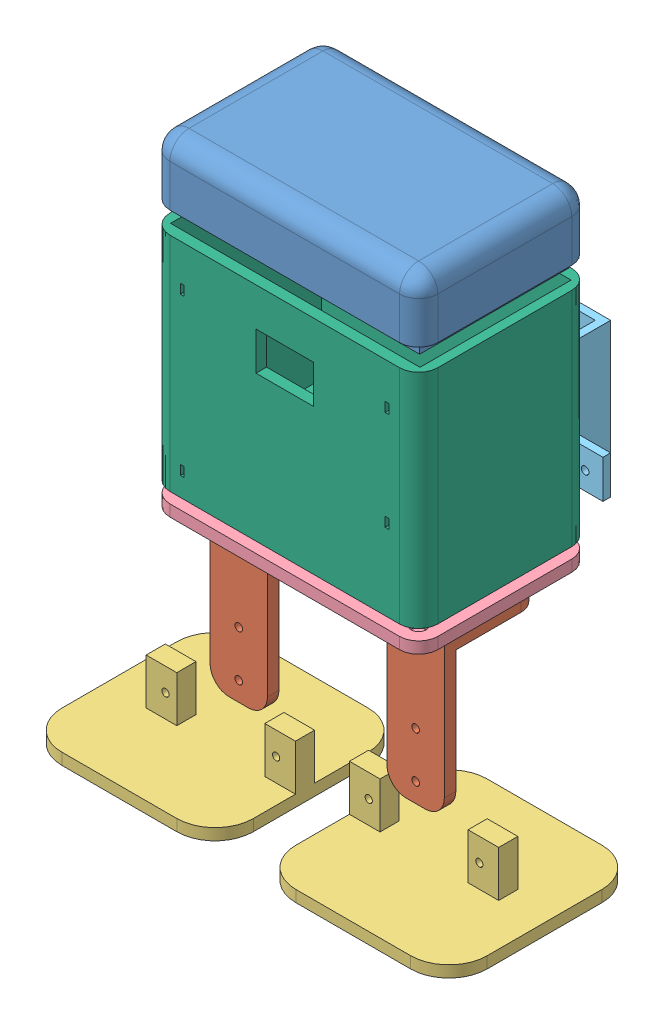
SolidWorks assembly 屏幕装配体, configuration 默认. Lengths in mm.
Overall size (111.6 142.57 75.38).
8 component instances, 6 part files, 9 mates.
Components (placement in the parent):
- 额头-1: 额头 [默认] at (-6.3922 22.1994 70) x (-1 0 0) z (0 0 1) size (70 19 45)
- 腿-1: 腿 [默认] at (-36.8922 -91.2045 78.5) size (15 40 25)
- 腿-2: 腿 [默认] at (9.1078 -91.2045 78.2863) size (15 40 25)
- 脚-1: 脚 [默认] at (-36.3796 -104.3715 80.706) size (50 15 50)
- 脚-2: 脚 [默认] at (25.2173 -104.3715 81.2042) x (-1 0 0) z (0 0 -1) size (50 15 50)
- 身体下-1: 身体下 [默认] at (-6.3922 -47.2775 70) size (70 3 45)
- 电池盖板-2: 电池盖板 [默认] at (-23.4463 -36.8498 32.82) x (-1 0 0) z (0 0 -1) size (67.96 30 12)
- 身体上-屏幕-1: 身体上-屏幕 [默认] at (-6.3922 -41.472 70) size (70 58 45)
Mates (geometry in assembly coordinates):
- 重合7: coincident aligned: plane of 腿-1 through (-36.8922 -51.2045 81.5) normal (0 1 0); plane of 腿-2 through (9.1078 -51.2045 81.2863) normal (0 1 0)
- 重合8: coincident aligned: plane of 脚-1 through (-21.3796 -104.3715 65.706) normal (0 -1 0); plane of 脚-2 through (10.2173 -104.3715 96.2042) normal (0 -1 0)
- 重合9: coincident anti-aligned: plane of 腿-1 through (-36.8922 -86.2045 81.5) normal (-1 0 0); plane of 身体下-1 through (-36.8922 -54.2775 58.5) normal (1 0 0)
- 重合10: coincident anti-aligned: plane of 腿-1 through (-31.8922 -86.2045 81.5) normal (0 0 1); plane of 身体下-1 through (-36.8922 -54.2775 81.5) normal (0 0 -1)
- 重合12: coincident anti-aligned: plane of 腿-2 through (24.1078 -86.2045 81.2863) normal (1 0 0); plane of 身体下-1 through (24.1078 -54.2775 58.5) normal (-1 0 0)
- 重合13: coincident: plane of 身体下-1 through (-41.3922 -44.2775 47.5) normal (-1 0 0); plane of 身体上-屏幕-1 through (-41.3922 -38.472 47.5) normal (-1 0 0)
- 重合14: coincident aligned: plane of 身体下-1 through (-41.3922 -44.2775 92.5) normal (0 0 1); plane of 身体上-屏幕-1 through (-41.3922 -38.472 92.5) normal (0 0 1)
- 重合15: coincident: plane of 额头-1 through (28.6078 37.1994 92.5) normal (0 0 1); plane of 身体上-屏幕-1 through (-41.3922 -38.472 92.5) normal (0 0 1)
- 重合16: coincident aligned: plane of 额头-1 through (28.6078 37.1994 92.5) normal (1 0 0); plane of 身体上-屏幕-1 through (28.6078 -38.472 47.5) normal (1 0 0)
